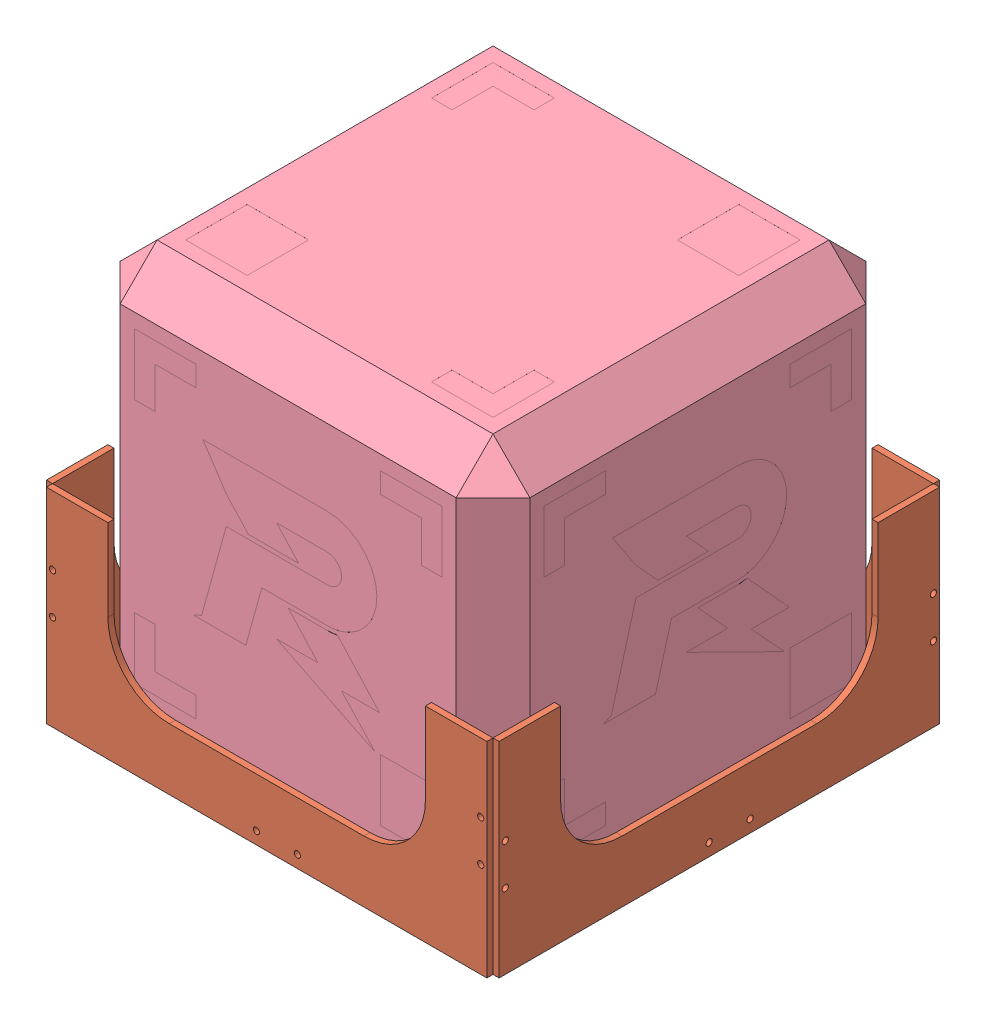
SolidWorks assembly 矿仓1.0, configuration 默认. Lengths in mm.
Overall size (221 203 221).
11 component instances, 4 part files, 29 mates.
Components (placement in the parent):
- 矿仓底板-1: 矿仓底板 [默认] x (1 0 0) z (0 -1 0) size (215 215 3)
- 矿仓侧板-1: 矿仓侧板 [前] at (0 48.5 109) x (-1 0 0) z (0 0 -1) size (215 100 3)
- 矿仓侧板-2: 矿仓侧板 [后] at (109 48.5 0) x (0 0 1) z (-1 0 0) size (215 100 3)
- 矿仓侧板-3: 矿仓侧板 [前] at (0 48.5 -109) x (-1 0 0) z (0 0 -1) size (215 100 3)
- 矿仓侧板-4: 矿仓侧板 [后] at (-109 48.5 0) x (0 0 1) z (-1 0 0) size (215 100 3)
- 四孔直角转接件-1: 四孔直角转接件 [上交角件] at (0 4.5 -104.5) x (0 0 1) z (-1 0 0) size (6 6 40)
- 四孔直角转接件-2: 四孔直角转接件 [上交角件] at (0 4.5 104.5) x (0 0 1) z (-1 0 0) size (6 6 40)
- 四孔直角转接件-3: 四孔直角转接件 [上交角件] at (-104.5 4.5 0) size (6 6 40)
- 四孔直角转接件-4: 四孔直角转接件 [上交角件] at (104.5 4.5 0) size (6 6 40)
- 四孔直角转接件-5: 四孔直角转接件 [上交角件] at (104.5 50 -104.5) x (0 0 1) z (0 -1 0) size (6 6 40)
- 金矿-2: 金矿 [默认] at (0 19.5 0) size (200 200 200)
Mates (geometry in assembly coordinates):
- 重合6: coincident anti-aligned: plane of 矿仓底板-1 through (-107.5 -1.5 -107.5) normal (0 0 -1); plane of 矿仓侧板-3 through (0 48.5 -107.5) normal (0 0 1)
- 重合8: coincident aligned: plane of 矿仓底板-1 through (0 -1.5 0) normal (0 -1 0); plane of 矿仓侧板-3 through (107.5 -1.5 -110.5) normal (0 -1 0)
- 重合9: coincident anti-aligned: plane of 矿仓底板-1 through (-107.5 -1.5 -107.5) normal (-1 0 0); plane of 矿仓侧板-4 through (-107.5 48.5 0) normal (1 0 0)
- 重合10: coincident anti-aligned: plane of 矿仓侧板-3 through (0 48.5 -107.5) normal (0 0 1); plane of 矿仓侧板-4 through (-110.5 -1.5 -107.5) normal (0 0 -1)
- 重合11: coincident aligned: plane of 矿仓底板-1 through (0 -1.5 0) normal (0 -1 0); plane of 矿仓侧板-4 through (-110.5 -1.5 -107.5) normal (0 -1 0)
- 重合13: coincident anti-aligned: plane of 矿仓底板-1 through (0 1.5 0) normal (0 1 0); plane of 四孔直角转接件-1 through (-20 1.5 -107.5) normal (0 -1 0)
- 重合14: coincident anti-aligned: plane of 矿仓侧板-3 through (0 48.5 -107.5) normal (0 0 1); plane of 四孔直角转接件-1 through (-20 1.5 -107.5) normal (0 0 -1)
- 重合15: coincident anti-aligned: plane of 矿仓底板-1 through (-107.5 -1.5 107.5) normal (0 0 1); plane of 矿仓侧板-1 through (0 48.5 107.5) normal (0 0 -1)
- 重合16: coincident aligned: plane of 矿仓底板-1 through (0 -1.5 0) normal (0 -1 0); plane of 矿仓侧板-1 through (107.5 -1.5 107.5) normal (0 -1 0)
- 重合17: coincident anti-aligned: plane of 矿仓侧板-1 through (0 48.5 109) normal (-1 0 0)
- 重合18: coincident anti-aligned: plane of 矿仓底板-1 through (0 1.5 0) normal (0 1 0); plane of 四孔直角转接件-2 through (-20 1.5 101.5) normal (0 -1 0)
- 重合19: coincident anti-aligned: plane of 矿仓侧板-1 through (0 48.5 107.5) normal (0 0 -1); plane of 四孔直角转接件-2 through (-20 1.5 107.5) normal (0 0 1)
- 同心1: concentric anti-aligned: cylinder of 矿仓侧板-1 through (-5 4.5 100.5) axis (0 0 1) radius 1.525; cylinder of 四孔直角转接件-2 through (-5 4.5 101.5) axis (0 0 -1) radius 1.25
- 重合20: coincident anti-aligned: plane of 矿仓侧板-4 through (-107.5 48.5 0) normal (1 0 0); plane of 四孔直角转接件-3 through (-107.5 1.5 20) normal (-1 0 0)
- 重合21: coincident anti-aligned: plane of 矿仓底板-1 through (0 1.5 0) normal (0 1 0); plane of 四孔直角转接件-3 through (-107.5 1.5 20) normal (0 -1 0)
- 对称1: symmetric aligned: plane of 四孔直角转接件-3 through (-104.5 4.5 -20) normal (0 0 -1); plane of 四孔直角转接件-3 through (-104.5 4.5 20) normal (0 0 1)
- 重合22: coincident anti-aligned: plane of 矿仓底板-1 through (107.5 -1.5 -107.5) normal (1 0 0); plane of 矿仓侧板-2 through (107.5 48.5 0) normal (-1 0 0)
- 重合23: coincident aligned: plane of 矿仓底板-1 through (0 -1.5 0) normal (0 -1 0); plane of 矿仓侧板-2 through (107.5 -1.5 -107.5) normal (0 -1 0)
- 重合24: coincident aligned: plane of 矿仓侧板-2 through (109 48.5 0) normal (0 0 1)
- 对称2: symmetric aligned: plane of 四孔直角转接件-1 through (-20 4.5 -104.5) normal (-1 0 0); plane of 四孔直角转接件-1 through (20 4.5 -104.5) normal (1 0 0)
- 重合25: coincident anti-aligned: plane of 矿仓底板-1 through (0 1.5 0) normal (0 1 0); plane of 四孔直角转接件-4 through (101.5 1.5 20) normal (0 -1 0)
- 重合26: coincident anti-aligned: plane of 矿仓侧板-2 through (107.5 48.5 0) normal (-1 0 0); plane of 四孔直角转接件-4 through (107.5 1.5 20) normal (1 0 0)
- 重合27: coincident aligned: plane of 四孔直角转接件-4 through (104.5 4.5 0) normal (0 0 1)
- 重合28: coincident anti-aligned: plane of 矿仓侧板-3 through (0 48.5 -107.5) normal (0 0 1); plane of 四孔直角转接件-5 through (107.5 30 -107.5) normal (0 0 -1)
- 重合29: coincident anti-aligned: plane of 矿仓侧板-2 through (107.5 48.5 0) normal (-1 0 0); plane of 四孔直角转接件-5 through (107.5 30 -107.5) normal (1 0 0)
- 宽度6: width aligned: plane of 矿仓底板-1 through (0 1.5 0) normal (0 1 0); plane of 矿仓侧板-2 through (107.5 98.5 -107.5) normal (0 1 0); plane of 四孔直角转接件-5 through (104.5 70 -104.5) normal (0 1 0); plane of 四孔直角转接件-5 through (104.5 30 -104.5) normal (0 -1 0)
- 宽度7: width anti-aligned: plane of 矿仓侧板-2 through (107.5 48.5 0) normal (-1 0 0); plane of 金矿-2 through (-107.5 48.5 0) normal (1 0 0); plane of 矿仓侧板-4 through (100 183.5 82) normal (1 0 0); plane of 金矿-2 through (-100 183.5 82) normal (-1 0 0)
- 宽度8: width anti-aligned: plane of 矿仓侧板-3 through (0 48.5 -107.5) normal (0 0 1); plane of 金矿-2 through (0 48.5 107.5) normal (0 0 -1); plane of 矿仓侧板-1 through (-82 183.5 -100) normal (0 0 -1); plane of 金矿-2 through (-82 183.5 100) normal (0 0 1)
- 重合30: coincident anti-aligned: plane of 矿仓底板-1 through (0 1.5 0) normal (0 1 0); plane of 金矿-2 through (0 1.5 0) normal (0 -1 0)
